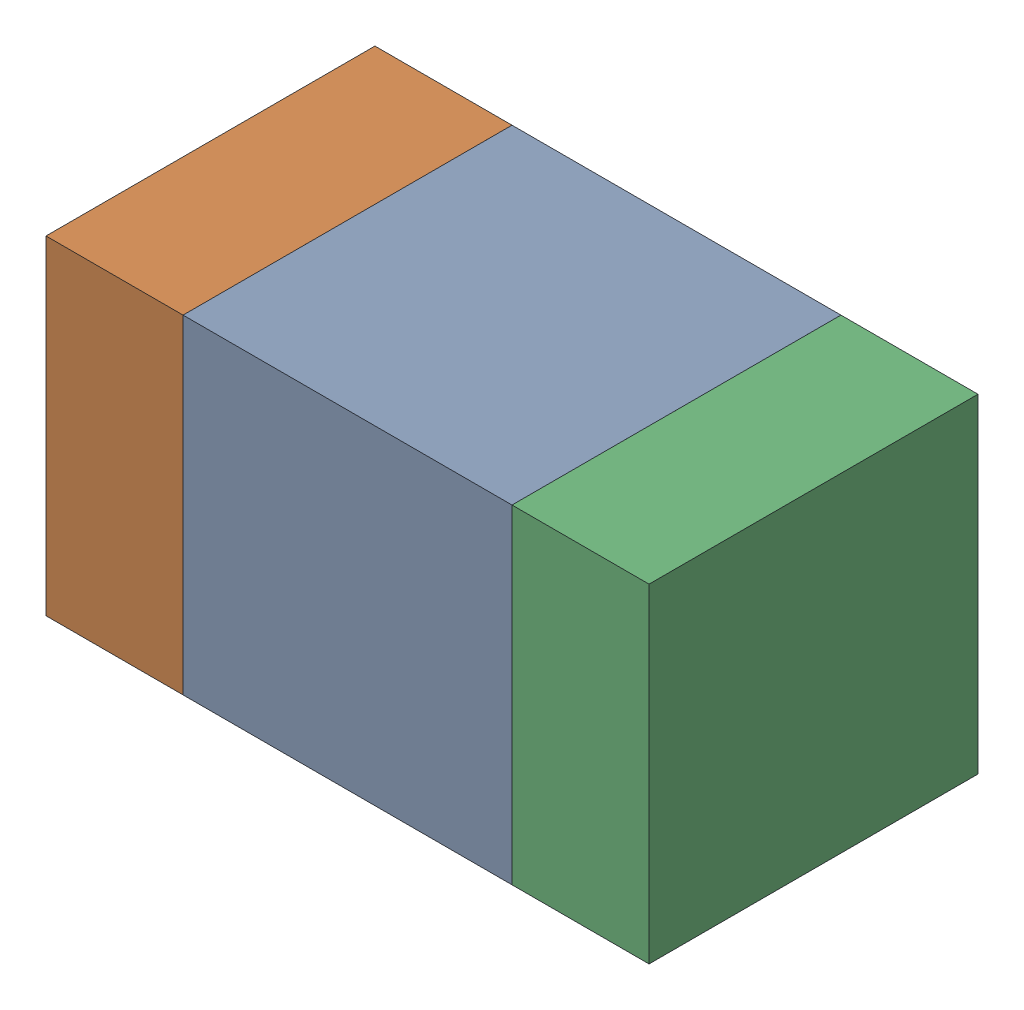
SolidWorks assembly C302_2PCB, configuration Default. Lengths in mm.
Overall size (1.1 0.6 0.6).
6 component instances, 2 part files, 0 mates.
Components (placement in the parent):
- 761606048-1: 761606048 [Default] at (142.7 102.4 0) size (0.6 0.6 0.6)
  - Extruded_9-1: Extruded_9 [Default] at origin size (0.6 0.6 0.6)
- 854785160-1: 854785160 [Default] at (142.275 102.4 0) size (0.25 0.6 0.6)
  - Extruded_19-1: Extruded_19 [Default] at origin size (0.25 0.6 0.6)
- 854785160-2: 854785160 [Default] at (143.125 102.4 0) size (0.25 0.6 0.6)
  - Extruded_19-1: Extruded_19 [Default] at origin size (0.25 0.6 0.6)
